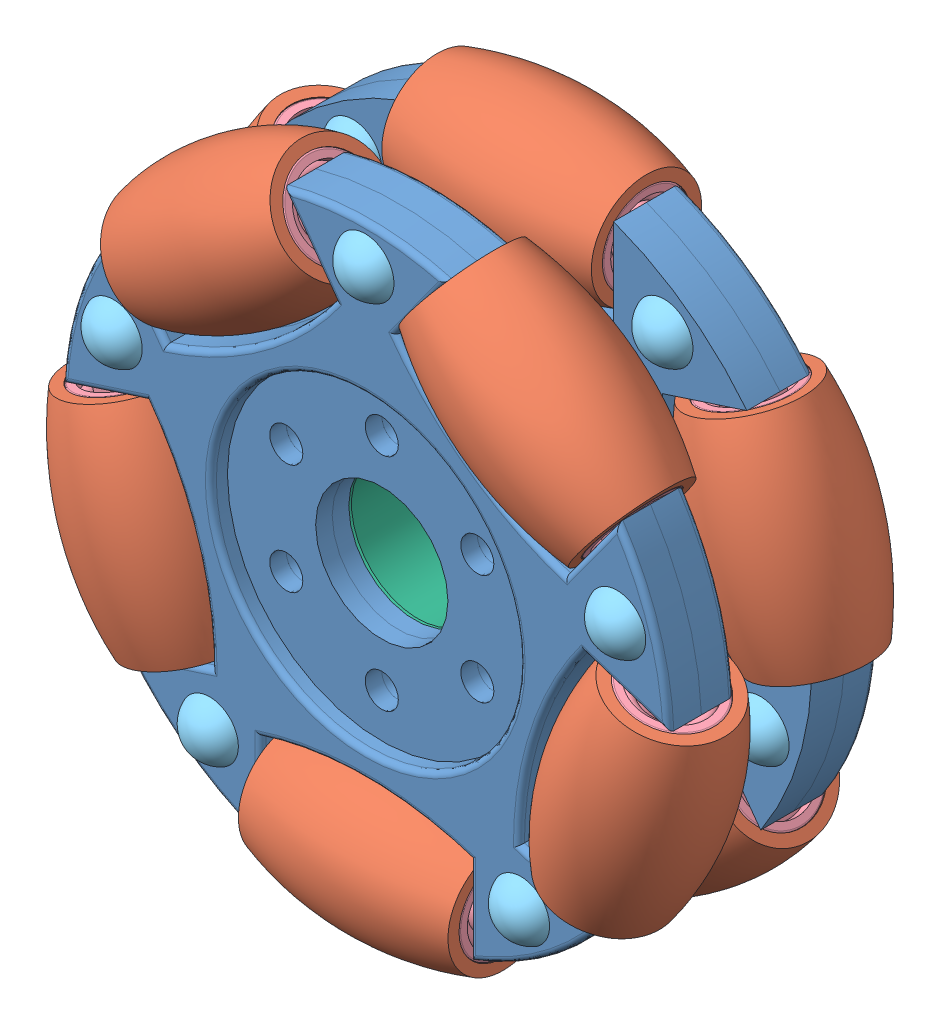
SolidWorks assembly Fianl Assembly, configuration Default. Lengths in mm.
Overall size (65.58 62.94 28.81).
67 component instances, 6 part files, 6 mates.
Components (placement in the parent):
- Plate Assembly-1: Plate Assembly [Default] at origin size (65.58 62.37 15.81)
  - Plate-1: Plate [Default] at (19.0254 28.4997 42.1698) size (54.96 53.31 3)
  - Plate-3: Plate [Default] at (19.0254 28.4997 48.1698) x (-1 0 0) z (0 0 -1) size (54.96 53.31 3)
  - Roller assenbly-1: Roller assenbly [Default] at (9.5254 51.4997 45.1698) x (1 0 0) z (0 -0.968969 -0.247184) size (22 13 13)
    - Roller-1: Roller [Default] at origin size (19 13 13)
    - Pin-1: Pin [Default] at (9.5 0 0) x (0 -0.246767 -0.969075) z (1 0 0) size (3 3 22)
    - instrument ball bearing_68_am-1: instrument ball bearing_68_am [AFBMA 12.1.4.1 - 0030-8 - 8,SI,NC,8_68] at (17.5 0 0) size (3 8 8)
    - instrument ball bearing_68_am-2: instrument ball bearing_68_am [AFBMA 12.1.4.1 - 0030-8 - 8,SI,NC,8_68] at (1.5 0 0) x (-1 0 0) z (0 -0.924225 -0.381849) size (3 8 8)
  - Roller assenbly-2: Roller assenbly [Default] at (-5.7846 26.5721 45.1698) x (0.309017 0.951057 0) z (0.921544 -0.299428 -0.247184) size (22 13 13)
    - Roller-1: Roller [Default] at origin size (19 13 13)
    - Pin-1: Pin [Default] at (9.5 0 0) x (0 -0.246767 -0.969075) z (1 0 0) size (3 3 22)
    - instrument ball bearing_68_am-1: instrument ball bearing_68_am [AFBMA 12.1.4.1 - 0030-8 - 8,SI,NC,8_68] at (17.5 0 0) size (3 8 8)
    - instrument ball bearing_68_am-2: instrument ball bearing_68_am [AFBMA 12.1.4.1 - 0030-8 - 8,SI,NC,8_68] at (1.5 0 0) x (-1 0 0) z (0 -0.924225 -0.381849) size (3 8 8)
  - Roller assenbly-3: Roller assenbly [Default] at (13.192 4.3084 45.1698) x (-0.809017 0.587785 0) z (0.569545 0.783912 -0.247184) size (22 13 13)
    - Roller-1: Roller [Default] at origin size (19 13 13)
    - Pin-1: Pin [Default] at (9.5 0 0) x (0 -0.246767 -0.969075) z (1 0 0) size (3 3 22)
    - instrument ball bearing_68_am-1: instrument ball bearing_68_am [AFBMA 12.1.4.1 - 0030-8 - 8,SI,NC,8_68] at (17.5 0 0) size (3 8 8)
    - instrument ball bearing_68_am-2: instrument ball bearing_68_am [AFBMA 12.1.4.1 - 0030-8 - 8,SI,NC,8_68] at (1.5 0 0) x (-1 0 0) z (0 -0.924225 -0.381849) size (3 8 8)
  - Roller assenbly-4: Roller assenbly [Default] at (40.2301 15.4763 45.1698) x (-0.809017 -0.587785 0) z (-0.569545 0.783912 -0.247184) size (22 13 13)
    - Roller-1: Roller [Default] at origin size (19 13 13)
    - Pin-1: Pin [Default] at (9.5 0 0) x (0 -0.246767 -0.969075) z (1 0 0) size (3 3 22)
    - instrument ball bearing_68_am-1: instrument ball bearing_68_am [AFBMA 12.1.4.1 - 0030-8 - 8,SI,NC,8_68] at (17.5 0 0) size (3 8 8)
    - instrument ball bearing_68_am-2: instrument ball bearing_68_am [AFBMA 12.1.4.1 - 0030-8 - 8,SI,NC,8_68] at (1.5 0 0) x (-1 0 0) z (0 -0.924225 -0.381849) size (3 8 8)
  - Roller assenbly-5: Roller assenbly [Default] at (37.964 44.6422 45.1698) x (0.309017 -0.951057 0) z (-0.921544 -0.299428 -0.247184) size (22 13 13)
    - Roller-1: Roller [Default] at origin size (19 13 13)
    - Pin-1: Pin [Default] at (9.5 0 0) x (0 -0.246767 -0.969075) z (1 0 0) size (3 3 22)
    - instrument ball bearing_68_am-1: instrument ball bearing_68_am [AFBMA 12.1.4.1 - 0030-8 - 8,SI,NC,8_68] at (17.5 0 0) size (3 8 8)
    - instrument ball bearing_68_am-2: instrument ball bearing_68_am [AFBMA 12.1.4.1 - 0030-8 - 8,SI,NC,8_68] at (1.5 0 0) x (-1 0 0) z (0 -0.924225 -0.381849) size (3 8 8)
  - rivet 02_din-7: rivet 02_din [DIN 660-3x10-St-A-5.5] at (33.1322 47.9161 42.6698) x (0 0 -1) z (1 0 0) size (9.1 5.2 5.2)
  - rivet 02_din-8: rivet 02_din [DIN 660-3x10-St-A-5.5] at (4.9185 47.9161 42.6698) x (0 0 -1) z (0.309017 0.951057 0) size (9.1 5.2 5.2)
  - rivet 02_din-9: rivet 02_din [DIN 660-3x10-St-A-5.5] at (-3.8 21.0833 42.6698) x (0 0 -1) z (-0.809017 0.587785 0) size (9.1 5.2 5.2)
  - rivet 02_din-10: rivet 02_din [DIN 660-3x10-St-A-5.5] at (19.0254 4.4997 42.6698) x (0 0 -1) z (-0.809017 -0.587785 0) size (9.1 5.2 5.2)
  - rivet 02_din-11: rivet 02_din [DIN 660-3x10-St-A-5.5] at (41.8507 21.0833 42.6698) x (0 0 -1) z (0.309017 -0.951057 0) size (9.1 5.2 5.2)
- Bush-1: Bush [Default] at (19.0254 28.4997 51.6698) size (28 28 10)
- Plate Assembly-5: Plate Assembly [Default] at (38.0508 56.9995 13) x (-1 0 0) z (0 0 1) size (65.58 62.37 15.81)
  - Plate-1: Plate [Default] at (19.0254 28.4997 42.1698) size (54.96 53.31 3)
  - Plate-3: Plate [Default] at (19.0254 28.4997 48.1698) x (-1 0 0) z (0 0 -1) size (54.96 53.31 3)
  - Roller assenbly-1: Roller assenbly [Default] at (9.5254 51.4997 45.1698) x (1 0 0) z (0 -0.968969 -0.247184) size (22 13 13)
    - Roller-1: Roller [Default] at origin size (19 13 13)
    - Pin-1: Pin [Default] at (9.5 0 0) x (0 -0.246767 -0.969075) z (1 0 0) size (3 3 22)
    - instrument ball bearing_68_am-1: instrument ball bearing_68_am [AFBMA 12.1.4.1 - 0030-8 - 8,SI,NC,8_68] at (17.5 0 0) size (3 8 8)
    - instrument ball bearing_68_am-2: instrument ball bearing_68_am [AFBMA 12.1.4.1 - 0030-8 - 8,SI,NC,8_68] at (1.5 0 0) x (-1 0 0) z (0 -0.924225 -0.381849) size (3 8 8)
  - Roller assenbly-2: Roller assenbly [Default] at (-5.7846 26.5721 45.1698) x (0.309017 0.951057 0) z (0.921544 -0.299428 -0.247184) size (22 13 13)
    - Roller-1: Roller [Default] at origin size (19 13 13)
    - Pin-1: Pin [Default] at (9.5 0 0) x (0 -0.246767 -0.969075) z (1 0 0) size (3 3 22)
    - instrument ball bearing_68_am-1: instrument ball bearing_68_am [AFBMA 12.1.4.1 - 0030-8 - 8,SI,NC,8_68] at (17.5 0 0) size (3 8 8)
    - instrument ball bearing_68_am-2: instrument ball bearing_68_am [AFBMA 12.1.4.1 - 0030-8 - 8,SI,NC,8_68] at (1.5 0 0) x (-1 0 0) z (0 -0.924225 -0.381849) size (3 8 8)
  - Roller assenbly-3: Roller assenbly [Default] at (13.192 4.3084 45.1698) x (-0.809017 0.587785 0) z (0.569545 0.783912 -0.247184) size (22 13 13)
    - Roller-1: Roller [Default] at origin size (19 13 13)
    - Pin-1: Pin [Default] at (9.5 0 0) x (0 -0.246767 -0.969075) z (1 0 0) size (3 3 22)
    - instrument ball bearing_68_am-1: instrument ball bearing_68_am [AFBMA 12.1.4.1 - 0030-8 - 8,SI,NC,8_68] at (17.5 0 0) size (3 8 8)
    - instrument ball bearing_68_am-2: instrument ball bearing_68_am [AFBMA 12.1.4.1 - 0030-8 - 8,SI,NC,8_68] at (1.5 0 0) x (-1 0 0) z (0 -0.924225 -0.381849) size (3 8 8)
  - Roller assenbly-4: Roller assenbly [Default] at (40.2301 15.4763 45.1698) x (-0.809017 -0.587785 0) z (-0.569545 0.783912 -0.247184) size (22 13 13)
    - Roller-1: Roller [Default] at origin size (19 13 13)
    - Pin-1: Pin [Default] at (9.5 0 0) x (0 -0.246767 -0.969075) z (1 0 0) size (3 3 22)
    - instrument ball bearing_68_am-1: instrument ball bearing_68_am [AFBMA 12.1.4.1 - 0030-8 - 8,SI,NC,8_68] at (17.5 0 0) size (3 8 8)
    - instrument ball bearing_68_am-2: instrument ball bearing_68_am [AFBMA 12.1.4.1 - 0030-8 - 8,SI,NC,8_68] at (1.5 0 0) x (-1 0 0) z (0 -0.924225 -0.381849) size (3 8 8)
  - Roller assenbly-5: Roller assenbly [Default] at (37.964 44.6422 45.1698) x (0.309017 -0.951057 0) z (-0.921544 -0.299428 -0.247184) size (22 13 13)
    - Roller-1: Roller [Default] at origin size (19 13 13)
    - Pin-1: Pin [Default] at (9.5 0 0) x (0 -0.246767 -0.969075) z (1 0 0) size (3 3 22)
    - instrument ball bearing_68_am-1: instrument ball bearing_68_am [AFBMA 12.1.4.1 - 0030-8 - 8,SI,NC,8_68] at (17.5 0 0) size (3 8 8)
    - instrument ball bearing_68_am-2: instrument ball bearing_68_am [AFBMA 12.1.4.1 - 0030-8 - 8,SI,NC,8_68] at (1.5 0 0) x (-1 0 0) z (0 -0.924225 -0.381849) size (3 8 8)
  - rivet 02_din-7: rivet 02_din [DIN 660-3x10-St-A-5.5] at (33.1322 47.9161 42.6698) x (0 0 -1) z (1 0 0) size (9.1 5.2 5.2)
  - rivet 02_din-8: rivet 02_din [DIN 660-3x10-St-A-5.5] at (4.9185 47.9161 42.6698) x (0 0 -1) z (0.309017 0.951057 0) size (9.1 5.2 5.2)
  - rivet 02_din-9: rivet 02_din [DIN 660-3x10-St-A-5.5] at (-3.8 21.0833 42.6698) x (0 0 -1) z (-0.809017 0.587785 0) size (9.1 5.2 5.2)
  - rivet 02_din-10: rivet 02_din [DIN 660-3x10-St-A-5.5] at (19.0254 4.4997 42.6698) x (0 0 -1) z (-0.809017 -0.587785 0) size (9.1 5.2 5.2)
  - rivet 02_din-11: rivet 02_din [DIN 660-3x10-St-A-5.5] at (41.8507 21.0833 42.6698) x (0 0 -1) z (0.309017 -0.951057 0) size (9.1 5.2 5.2)
Mates (geometry in assembly coordinates):
- Concentric6: concentric anti-aligned: cylinder of Plate Assembly-1/Plate-1 through (19.0254 28.4997 42.1698) axis (0 0 1) radius 6; cylinder of Bush-1 through (19.0254 28.4997 56.6698) axis (0 0 -1) radius 6
- Coincident4: coincident anti-aligned: plane of Plate Assembly-1/Plate-3 through (19.0254 28.4997 46.6698) normal (0 0 1); plane of Bush-1 through (19.0254 28.4997 46.6698) normal (0 0 -1)
- Concentric9: concentric aligned: cylinder of Plate Assembly-1/Plate-3 through (19.0254 38.4997 48.1698) axis (0 0 -1) radius 1.5; cylinder of Bush-1 through (19.0254 38.4997 56.6698) axis (0 0 -1) radius 1.5
- Concentric10: concentric anti-aligned: cylinder of Plate Assembly-1/Plate-3 through (19.0254 28.4997 45.1698) axis (0 0 1) radius 27.5; cylinder of Plate Assembly-5/Plate-1 through (19.0254 28.4997 58.1698) axis (0 0 -1) radius 27.5
- Coincident6: coincident anti-aligned: plane of Bush-1 through (19.0254 28.4997 56.6698) normal (0 0 1); plane of Plate Assembly-5/Plate-1 through (19.0254 28.4997 56.6698) normal (0 0 -1)
- Concentric11: concentric aligned: cylinder of Bush-1 through (19.0254 38.4997 56.6698) axis (0 0 -1) radius 1.5; cylinder of Plate Assembly-5/Plate-3 through (19.0254 38.4997 61.1698) axis (0 0 -1) radius 1.5
